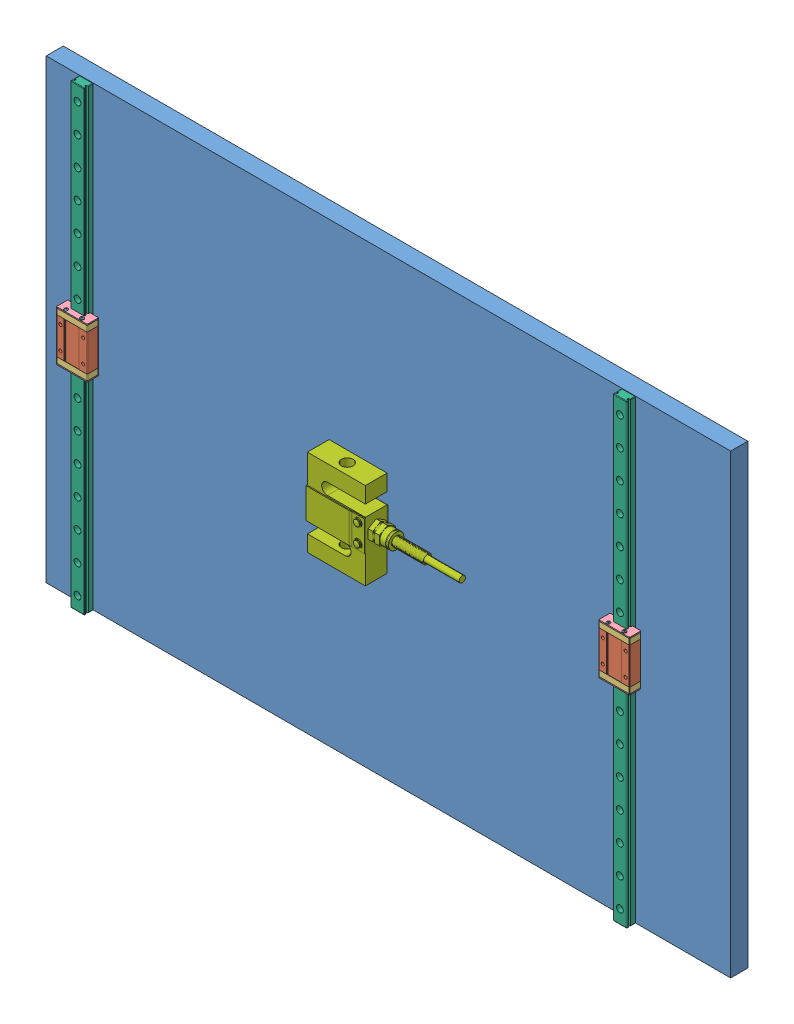
SolidWorks assembly Ensamblaje_WallBench_V2, configuration Predeterminado. Lengths in mm.
Overall size (1598.73 745.52 43.25).
24 component instances, 7 part files, 9 mates.
Components (placement in the parent):
- Wall-1: Wall [Predeterminado] at (-300 -200 -15) x (-1 0 0) z (0 0 1) size (600 400 15)
- Assem1-1: Assem1 [Default] at (-315.7379 -554.048 -166.1827) x (0 0 1) z (0 1 0) size (13 27 400)
  - Main Block-1: Main Block [Default] at (169.1827 226.6144 359.262) x (0 0 1) z (1 0 0) size (32 27 10)
  - Green End Cap-1: Green End Cap [Default] at (174.1827 226.6144 343.262) x (0 1 0) z (0 0 -1) size (27 10 5)
  - Red End Cap-1: Red End Cap [Default] at (174.1827 226.6144 338.262) x (0 1 0) z (0 0 -1) size (27 10 1)
  - Green End Cap-2: Green End Cap [Default] at (174.1827 226.6144 375.262) x (0 -1 0) z (0 0 1) size (27 10 5)
  - Red End Cap-2: Red End Cap [Default] at (174.1827 226.6144 380.262) x (0 -1 0) z (0 0 1) size (27 10 1)
  - Button M3x8-1: Button M3x8 [Default] at (177.1827 219.6144 381.762) x (0.381849 -0.924225 0) z (0 0 -1) size (3 3 7)
  - Button M3x8-2: Button M3x8 [Default] at (177.1827 233.6144 382.262) x (0.381849 -0.924225 0) z (0 0 -1) size (3 3 7)
  - Button M3x8-3: Button M3x8 [Default] at (177.1827 219.6144 336.762) x (-0.381849 0.924225 0) z (0 0 1) size (3 3 7)
  - Button M3x8-4: Button M3x8 [Default] at (177.1827 233.6144 336.762) x (-0.381849 0.924225 0) z (0 0 1) size (3 3 7)
  - Rail 400mm-1: Rail 400mm [Default] at (170.1827 226.6144 554.048) x (0 0 -1) z (1 0 0) size (400 12 8)
- Assem1-2: Assem1 [Default] at (-791.1689 -554.048 -166.1827) x (0 0 1) z (0 1 0) size (13 27 400)
  - Main Block-1: Main Block [Default] at (169.1827 226.6144 359.262) x (0 0 1) z (1 0 0) size (32 27 10)
  - Green End Cap-1: Green End Cap [Default] at (174.1827 226.6144 343.262) x (0 1 0) z (0 0 -1) size (27 10 5)
  - Red End Cap-1: Red End Cap [Default] at (174.1827 226.6144 338.262) x (0 1 0) z (0 0 -1) size (27 10 1)
  - Green End Cap-2: Green End Cap [Default] at (174.1827 226.6144 375.262) x (0 -1 0) z (0 0 1) size (27 10 5)
  - Red End Cap-2: Red End Cap [Default] at (174.1827 226.6144 380.262) x (0 -1 0) z (0 0 1) size (27 10 1)
  - Button M3x8-1: Button M3x8 [Default] at (177.1827 219.6144 381.762) x (0.381849 -0.924225 0) z (0 0 -1) size (3 3 7)
  - Button M3x8-2: Button M3x8 [Default] at (177.1827 233.6144 382.262) x (0.381849 -0.924225 0) z (0 0 -1) size (3 3 7)
  - Button M3x8-3: Button M3x8 [Default] at (177.1827 219.6144 336.762) x (-0.381849 0.924225 0) z (0 0 1) size (3 3 7)
  - Button M3x8-4: Button M3x8 [Default] at (177.1827 233.6144 336.762) x (-0.381849 0.924225 0) z (0 0 1) size (3 3 7)
  - Rail 400mm-1: Rail 400mm [Default] at (170.1827 226.6144 554.048) x (0 0 -1) z (1 0 0) size (400 12 8)
- S-beam_load_cell_FS6B-2: S-beam_load_cell_FS6B [默认] at (-320.383 -199.1371 15.75) size (1344.52 582.75 25)
Mates (geometry in assembly coordinates):
- Coincidente1: coincident anti-aligned: plane of Wall-1 through (-300 -200 0) normal (0 0 1); plane of Assem1-1/Rail 400mm-1 through (-83.1235 -400 0) normal (0 0 -1)
- Paralelo2: parallel anti-aligned: plane of Wall-1 through (0 -400 0) normal (1 0 0); plane of Assem1-1/Rail 400mm-1 through (-95.1235 -400 4.5) normal (-1 0 0)
- Coincidente3: coincident: point of Wall-1; point of assembly
- Coincidente4: coincident aligned: plane of Wall-1 through (0 -400 0) normal (0 -1 0); plane of Assem1-1/Rail 400mm-1 through (-89.1235 -400 4) normal (0 -1 0)
- Paralelo3: parallel anti-aligned: plane of Wall-1 through (-300 -200 -15) normal (0 0 -1); plane of assembly through (0 0 0) normal (0 0 1)
- Paralelo4: parallel anti-aligned: plane of Wall-1 through (0 -400 0) normal (0 -1 0); plane of assembly through (0 0 0) normal (0 1 0)
- Coincidente7: coincident anti-aligned: plane of Wall-1 through (-300 -200 0) normal (0 0 1); plane of Assem1-2/Rail 400mm-1 through (-558.5544 -400 0) normal (0 0 -1)
- Coincidente9: coincident aligned: plane of Wall-1 through (0 0 0) normal (0 1 0); plane of Assem1-2/Rail 400mm-1 through (-564.5544 0 4) normal (0 1 0)
- Distancia1: distance = 5 mm anti-aligned: plane of S-beam_load_cell_FS6B-2 through (-307.9363 -185.8871 5) normal (0 0 -1); plane of Wall-1 through (-300 -200 0) normal (0 0 1)
